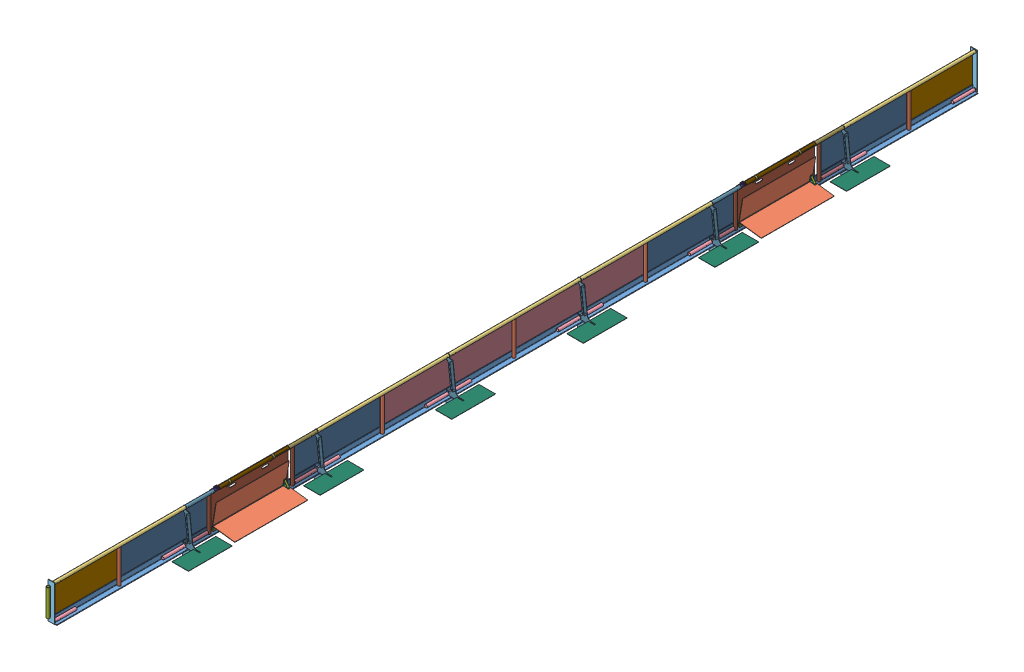
SolidWorks assembly FE-00038-02_ASM, configuration Default. Lengths in mm.
Overall size (415.19 551.39 12944.68).
137 component instances, 33 part files, 0 mates.
Components (placement in the parent):
- FE-00024_ASM-1: FE-00024_ASM [Default] at origin size (109.89 508 2063.85)
  - FE-00005_ASM-1: FE-00005_ASM [Default] at origin size (76.2 507.65 1828.8)
    - FE-00005-01-1: FE-00005-01 [Default] at origin size (76.2 76.2 1828.8)
    - FE-00005-03-1: FE-00005-03 [Default] at (27.432 6.35 914.4) size (42.16 471.23 42.16)
    - FE-00005-04-1: FE-00005-04 [Default] at (27.432 486.5688 0) size (42.16 42.16 1828.8)
    - FE-00005-02-1: FE-00005-02 [Default] at (27.432 27.432 1520.825) size (42.16 42.16 301.62)
    - FE-00005-02-2: FE-00005-02 [Default] at (27.432 27.432 307.975) x (1 0 0) z (0 0 -1) size (42.16 42.16 301.62)
  - FE-00018_ASM-1: FE-00018_ASM [Default] at (-33.6868 6.35 1835.15) size (88.9 501.65 152.5)
    - FE-00018-03-1: FE-00018-03 [Default] at origin size (88.9 501.65 6.35)
    - FE-00018-02-1: FE-00018-02 [Default] at (61.1187 480.2188 -101.6) size (33.4 33.4 101.6)
    - FE-00018-02-2: FE-00018-02 [Default] at (61.1124 21.4312 -101.6) size (33.4 33.4 101.6)
    - FE-00018-01-1: FE-00018-01 [Default] at (23.368 63.5 29.8196) x (1 0 0) z (0 1 0) size (42.16 42.16 374.65)
    - FE-00018-04-1: FE-00018-04 [Default] at (23.368 250.825 6.35) size (19.05 374.65 2.38)
  - FE-00026-1: FE-00026 [Default] at (27.432 486.5688 177.8) x (-1 0 0) z (0 0 -1) size (33.4 33.4 355.6)
- FE-00029_ASM-1: FE-00029_ASM [Default] at (0 0 -1833.5625) size (76.2 519.84 2184.4)
  - FE-00006_ASM-1: FE-00006_ASM [Default] at origin size (76.2 507.65 1828.8)
    - FE-00006-01-1: FE-00006-01 [Default] at origin size (76.2 76.2 1828.8)
    - FE-00006-10-1: FE-00006-10 [Default] at (27.432 6.35 1496.2188) size (42.16 471.23 42.16)
    - FE-00006-03-1: FE-00006-03 [Default] at (27.432 486.5688 393.7) x (1 0 0) z (0 0 -1) size (42.16 42.16 393.7)
    - FE-00006-02-1: FE-00006-02 [Default] at (27.432 27.432 1520.825) size (42.16 42.16 301.62)
    - FE-00006-02-2: FE-00006-02 [Default] at (27.432 27.432 307.975) x (1 0 0) z (0 0 -1) size (42.16 42.16 301.62)
    - FE-00006-10-2: FE-00006-10 [Default] at (27.432 6.35 332.5876) size (42.16 471.23 42.16)
    - FE-00006-05-1: FE-00006-05 [Default] at (27.432 486.5688 1435.1) size (42.16 42.16 393.7)
    - FE-00006-08-1: FE-00006-08 [Default] at (27.432 486.5688 381) size (48.26 22.22 25.4)
    - FE-00006-09-1: FE-00006-09 [Default] at (12.7 6.35 381) size (25.4 25.4 1066.8)
  - FE-00026-1: FE-00026 [Default] at (27.432 27.432 1651) size (33.4 33.4 355.6)
  - FE-00026-2: FE-00026 [Default] at (27.432 486.5688 177.8) x (1 0 0) z (0 0 -1) size (33.4 33.4 355.6)
  - FE-00027-1: FE-00027 [Default] at (29.0202 469.0397 1500.1875) x (1 0.000041 0) z (0 0.000003 1) size (15.88 50.56 126.92)
  - FE-00027-2: FE-00027 [Default] at (25.8452 469.039 1296.9875) x (-1 -0.000041 0) z (0 -0.000003 -1) size (15.88 50.56 126.92)
  - FE-00028-1: FE-00028 [Default] at (27.432 486.5728 879.1575) x (0 -0.000003 -1) z (1 0.000041 0) size (965.2 42.16 42.16)
  - FE-00031-1: FE-00031 [Default] at (27.432 486.5717 428.3075) x (0 0.000003 1) z (-1 -0.000041 0) size (304.8 33.4 33.4)
- FE-00022_ASM-1: FE-00022_ASM [Default] at (0 0 -3667.125) size (76.2 507.65 2184.4)
  - FE-00005_ASM-1: FE-00005_ASM [Default] at origin size (76.2 507.65 1828.8)
    - FE-00005-01-1: FE-00005-01 [Default] at origin size (76.2 76.2 1828.8)
    - FE-00005-03-1: FE-00005-03 [Default] at (27.432 6.35 914.4) size (42.16 471.23 42.16)
    - FE-00005-04-1: FE-00005-04 [Default] at (27.432 486.5688 0) size (42.16 42.16 1828.8)
    - FE-00005-02-1: FE-00005-02 [Default] at (27.432 27.432 1520.825) size (42.16 42.16 301.62)
    - FE-00005-02-2: FE-00005-02 [Default] at (27.432 27.432 307.975) x (1 0 0) z (0 0 -1) size (42.16 42.16 301.62)
  - FE-00026-1: FE-00026 [Default] at (27.432 27.432 1651) size (33.4 33.4 355.6)
  - FE-00026-2: FE-00026 [Default] at (27.432 486.5688 177.8) x (-1 0 0) z (0 0 -1) size (33.4 33.4 355.6)
- FE-00022_ASM-2: FE-00022_ASM [Default] at (0 0 -5500.6875) size (76.2 507.65 2184.4)
  - FE-00005_ASM-1: FE-00005_ASM [Default] at origin size (76.2 507.65 1828.8)
    - FE-00005-01-1: FE-00005-01 [Default] at origin size (76.2 76.2 1828.8)
    - FE-00005-03-1: FE-00005-03 [Default] at (27.432 6.35 914.4) size (42.16 471.23 42.16)
    - FE-00005-04-1: FE-00005-04 [Default] at (27.432 486.5688 0) size (42.16 42.16 1828.8)
    - FE-00005-02-1: FE-00005-02 [Default] at (27.432 27.432 1520.825) size (42.16 42.16 301.62)
    - FE-00005-02-2: FE-00005-02 [Default] at (27.432 27.432 307.975) x (1 0 0) z (0 0 -1) size (42.16 42.16 301.62)
  - FE-00026-1: FE-00026 [Default] at (27.432 27.432 1651) size (33.4 33.4 355.6)
  - FE-00026-2: FE-00026 [Default] at (27.432 486.5688 177.8) x (-1 0 0) z (0 0 -1) size (33.4 33.4 355.6)
- FE-00022_ASM-3: FE-00022_ASM [Default] at (0 0 -7334.25) size (76.2 507.65 2184.4)
  - FE-00005_ASM-1: FE-00005_ASM [Default] at origin size (76.2 507.65 1828.8)
    - FE-00005-01-1: FE-00005-01 [Default] at origin size (76.2 76.2 1828.8)
    - FE-00005-03-1: FE-00005-03 [Default] at (27.432 6.35 914.4) size (42.16 471.23 42.16)
    - FE-00005-04-1: FE-00005-04 [Default] at (27.432 486.5688 0) size (42.16 42.16 1828.8)
    - FE-00005-02-1: FE-00005-02 [Default] at (27.432 27.432 1520.825) size (42.16 42.16 301.62)
    - FE-00005-02-2: FE-00005-02 [Default] at (27.432 27.432 307.975) x (1 0 0) z (0 0 -1) size (42.16 42.16 301.62)
  - FE-00026-1: FE-00026 [Default] at (27.432 27.432 1651) size (33.4 33.4 355.6)
  - FE-00026-2: FE-00026 [Default] at (27.432 486.5688 177.8) x (-1 0 0) z (0 0 -1) size (33.4 33.4 355.6)
- FE-00029_ASM-2: FE-00029_ASM [Default] at (0 0 -9167.8125) size (76.2 519.84 2184.4)
  - FE-00006_ASM-1: FE-00006_ASM [Default] at origin size (76.2 507.65 1828.8)
    - FE-00006-01-1: FE-00006-01 [Default] at origin size (76.2 76.2 1828.8)
    - FE-00006-10-1: FE-00006-10 [Default] at (27.432 6.35 1496.2188) size (42.16 471.23 42.16)
    - FE-00006-03-1: FE-00006-03 [Default] at (27.432 486.5688 393.7) x (1 0 0) z (0 0 -1) size (42.16 42.16 393.7)
    - FE-00006-02-1: FE-00006-02 [Default] at (27.432 27.432 1520.825) size (42.16 42.16 301.62)
    - FE-00006-02-2: FE-00006-02 [Default] at (27.432 27.432 307.975) x (1 0 0) z (0 0 -1) size (42.16 42.16 301.62)
    - FE-00006-10-2: FE-00006-10 [Default] at (27.432 6.35 332.5876) size (42.16 471.23 42.16)
    - FE-00006-05-1: FE-00006-05 [Default] at (27.432 486.5688 1435.1) size (42.16 42.16 393.7)
    - FE-00006-08-1: FE-00006-08 [Default] at (27.432 486.5688 381) size (48.26 22.22 25.4)
    - FE-00006-09-1: FE-00006-09 [Default] at (12.7 6.35 381) size (25.4 25.4 1066.8)
  - FE-00026-1: FE-00026 [Default] at (27.432 27.432 1651) size (33.4 33.4 355.6)
  - FE-00026-2: FE-00026 [Default] at (27.432 486.5688 177.8) x (1 0 0) z (0 0 -1) size (33.4 33.4 355.6)
  - FE-00027-1: FE-00027 [Default] at (29.0202 469.0397 1500.1875) x (1 0.000041 0) z (0 0.000003 1) size (15.88 50.56 126.92)
  - FE-00027-2: FE-00027 [Default] at (25.8452 469.039 1296.9875) x (-1 -0.000041 0) z (0 -0.000003 -1) size (15.88 50.56 126.92)
  - FE-00028-1: FE-00028 [Default] at (27.432 486.5728 879.1575) x (0 -0.000003 -1) z (1 0.000041 0) size (965.2 42.16 42.16)
  - FE-00031-1: FE-00031 [Default] at (27.432 486.5717 428.3075) x (0 0.000003 1) z (-1 -0.000041 0) size (304.8 33.4 33.4)
- FE-00023_ASM-1: FE-00023_ASM [Default] at (0 0 -11001.375) size (109.88 508 2063.85)
  - FE-00005_ASM-1: FE-00005_ASM [Default] at origin size (76.2 507.65 1828.8)
    - FE-00005-01-1: FE-00005-01 [Default] at origin size (76.2 76.2 1828.8)
    - FE-00005-03-1: FE-00005-03 [Default] at (27.432 6.35 914.4) size (42.16 471.23 42.16)
    - FE-00005-04-1: FE-00005-04 [Default] at (27.432 486.5688 0) size (42.16 42.16 1828.8)
    - FE-00005-02-1: FE-00005-02 [Default] at (27.432 27.432 1520.825) size (42.16 42.16 301.62)
    - FE-00005-02-2: FE-00005-02 [Default] at (27.432 27.432 307.975) x (1 0 0) z (0 0 -1) size (42.16 42.16 301.62)
  - FE-00026-1: FE-00026 [Default] at (27.432 27.432 1651) size (33.4 33.4 355.6)
  - FE-00018_ASM-1: FE-00018_ASM [Default] at (-33.6804 508 -6.35) x (1 0 0) z (0 0 -1) size (88.9 501.65 152.5)
    - FE-00018-03-1: FE-00018-03 [Default] at origin size (88.9 501.65 6.35)
    - FE-00018-02-1: FE-00018-02 [Default] at (61.1187 480.2188 -101.6) size (33.4 33.4 101.6)
    - FE-00018-02-2: FE-00018-02 [Default] at (61.1124 21.4312 -101.6) size (33.4 33.4 101.6)
    - FE-00018-01-1: FE-00018-01 [Default] at (23.368 63.5 29.8196) x (1 0 0) z (0 1 0) size (42.16 42.16 374.65)
    - FE-00018-04-1: FE-00018-04 [Default] at (23.368 250.825 6.35) size (19.05 374.65 2.38)
- FE-00014_ASM-1: FE-00014_ASM [Default] at (26.1866 200.2901 -8253.4125) x (0 0 -1) z (-0.160398 -0.987052 0) size (1016 321.79 336.1)
  - FE-00014-01-1: FE-00014-01 [Default] at origin size (1016 4.76 304.8)
  - FE-00014-02_ASM-1: FE-00014-02_ASM [Default] at (0 -2.286 159.4485) x (1 0 0) z (0 -1 0) size (990.6 31.05 31.22)
    - 01_39_INCH-1: 01_39_INCH [Default] at origin size (990.6 30.86 10.92)
    - 02_39_INCH-1: 02_39_INCH [Default] at (0 5.4577 -5.6516) x (-1 0 0) z (0 0.999391 -0.034899) size (990.6 30.86 10.92)
    - 03_39_INCH-1: 03_39_INCH [Default] at (0 0 -5.461) size (990.6 6.35 6.35)
  - FE-00014-01-2: FE-00014-01 [Default] at (0 162.6372 157.0569) x (1 0 0) z (0 0.999391 -0.034899) size (1016 4.76 304.8)
  - FE-00014-04-1: FE-00014-04 [Default] at (482.6 4.7625 152.4) x (1 0 0) z (0 -1 0) size (25.4 76.2 76.2)
  - FE-00014-05-1: FE-00014-05 [Default] at (495.3 40.2983 116.8642) x (0 0.707107 0.707107) z (0 0.707107 -0.707107) size (82.55 25.4 25.4)
  - FE-00014-03-1: FE-00014-03 [Default] at (0 19.929 164.3278) x (1 0 0) z (0 -0.034899 -0.999391) size (990.6 19.05 19.05)
- FE-00014_ASM-2: FE-00014_ASM [Default] at (26.1866 200.2901 -919.1625) x (0 0 -1) z (-0.160398 -0.987052 0) size (1016 321.79 336.1)
  - FE-00014-01-1: FE-00014-01 [Default] at origin size (1016 4.76 304.8)
  - FE-00014-02_ASM-1: FE-00014-02_ASM [Default] at (0 -2.286 159.4485) x (1 0 0) z (0 -1 0) size (990.6 31.05 31.22)
    - 01_39_INCH-1: 01_39_INCH [Default] at origin size (990.6 30.86 10.92)
    - 02_39_INCH-1: 02_39_INCH [Default] at (0 5.4577 -5.6516) x (-1 0 0) z (0 0.999391 -0.034899) size (990.6 30.86 10.92)
    - 03_39_INCH-1: 03_39_INCH [Default] at (0 0 -5.461) size (990.6 6.35 6.35)
  - FE-00014-01-2: FE-00014-01 [Default] at (0 162.6372 157.0569) x (1 0 0) z (0 0.999391 -0.034899) size (1016 4.76 304.8)
  - FE-00014-04-1: FE-00014-04 [Default] at (482.6 4.7625 152.4) x (1 0 0) z (0 -1 0) size (25.4 76.2 76.2)
  - FE-00014-05-1: FE-00014-05 [Default] at (495.3 40.2983 116.8642) x (0 0.707107 0.707107) z (0 0.707107 -0.707107) size (82.55 25.4 25.4)
  - FE-00014-03-1: FE-00014-03 [Default] at (0 19.929 164.3278) x (1 0 0) z (0 -0.034899 -0.999391) size (990.6 19.05 19.05)
- FE-00008-1: FE-00008 [Default] at (-6.35 0 -10086.975) x (0 0 -1) z (1 0 0) size (914.4 482.6 6.35)
- FE-00009-1: FE-00009 [Default] at (-6.35 0 -8842.375) x (0 0 -1) z (1 0 0) size (1244.6 482.6 6.35)
- FE-00017_ASM-1: FE-00017_ASM [Default] at (-3.5242 9.5284 -7707.3125) x (0 0 -1) z (1 0 0) size (1092.2 501.65 55.56)
  - FE-00011-1: FE-00011 [Default] at origin size (1092.2 482.6 6.35)
  - FE-00016-1: FE-00016 [Default] at (850.9 412.75 6.35) x (-1 0 0) z (0 -1 0) size (25.4 49.21 88.9)
  - FE-00016-2: FE-00016 [Default] at (241.3 412.75 6.35) x (-1 0 0) z (0 -1 0) size (25.4 49.21 88.9)
- FE-00009-2: FE-00009 [Default] at (-6.35 0 -6426.9938) x (0 0 -1) z (1 0 0) size (1244.6 482.6 6.35)
- FE-00010-1: FE-00010 [Default] at (-6.35 0 -4591.05) size (6.35 482.6 1828.8)
- FE-00010-2: FE-00010 [Default] at (-6.35 0 -2757.4875) size (6.35 482.6 1828.8)
- FE-00009-3: FE-00009 [Default] at (-6.35 0 -1508.125) x (0 0 -1) z (1 0 0) size (1244.6 482.6 6.35)
- FE-00017_ASM-2: FE-00017_ASM [Default] at (-3.5242 9.5284 -373.0625) x (0 0 -1) z (1 0 0) size (1092.2 501.65 55.56)
  - FE-00011-1: FE-00011 [Default] at origin size (1092.2 482.6 6.35)
  - FE-00016-1: FE-00016 [Default] at (850.9 412.75 6.35) x (-1 0 0) z (0 -1 0) size (25.4 49.21 88.9)
  - FE-00016-2: FE-00016 [Default] at (241.3 412.75 6.35) x (-1 0 0) z (0 -1 0) size (25.4 49.21 88.9)
- FE-00008-2: FE-00008 [Default] at (-6.35 0 1828.8) x (0 0 -1) z (1 0 0) size (914.4 482.6 6.35)
- FE-00009-4: FE-00009 [Default] at (-6.35 0 914.4) x (0 0 -1) z (1 0 0) size (1244.6 482.6 6.35)
- FE-00050-1: FE-00050 [Default] at (6.858 -0.7747 -3.175) size (317.5 508 106.36)
- FE-00050-2: FE-00050 [Default] at (6.858 -0.7747 -1836.7375) size (317.5 508 106.36)
- FE-00050-3: FE-00050 [Default] at (6.858 -0.7747 -3670.3) size (317.5 508 106.36)
- FE-00050-4: FE-00050 [Default] at (6.858 -0.7747 -5503.8625) size (317.5 508 106.36)
- FE-00050-5: FE-00050 [Default] at (6.858 -0.7747 -7337.425) size (317.5 508 106.36)
- FE-00050-6: FE-00050 [Default] at (6.858 -0.7747 -9170.9875) size (317.5 508 106.36)
- FE-00015-1: FE-00015 [Default] at (267.208 42.0878 -2.3813) x (0 0 -1) z (1 0 0) size (609.6 3.18 228.6)
- FE-00015-2: FE-00015 [Default] at (267.208 42.0878 -1835.9501) x (0 0 -1) z (1 0 0) size (609.6 3.18 228.6)
- FE-00015-3: FE-00015 [Default] at (267.208 42.0878 -3669.5126) x (0 0 -1) z (1 0 0) size (609.6 3.18 228.6)
- FE-00015-4: FE-00015 [Default] at (267.208 42.0878 -5503.0751) x (0 0 -1) z (1 0 0) size (609.6 3.18 228.6)
- FE-00015-5: FE-00015 [Default] at (267.208 42.0878 -7336.6376) x (0 0 -1) z (1 0 0) size (609.6 3.18 228.6)
- FE-00015-6: FE-00015 [Default] at (267.208 42.0878 -9170.2001) x (0 0 -1) z (1 0 0) size (609.6 3.18 228.6)
